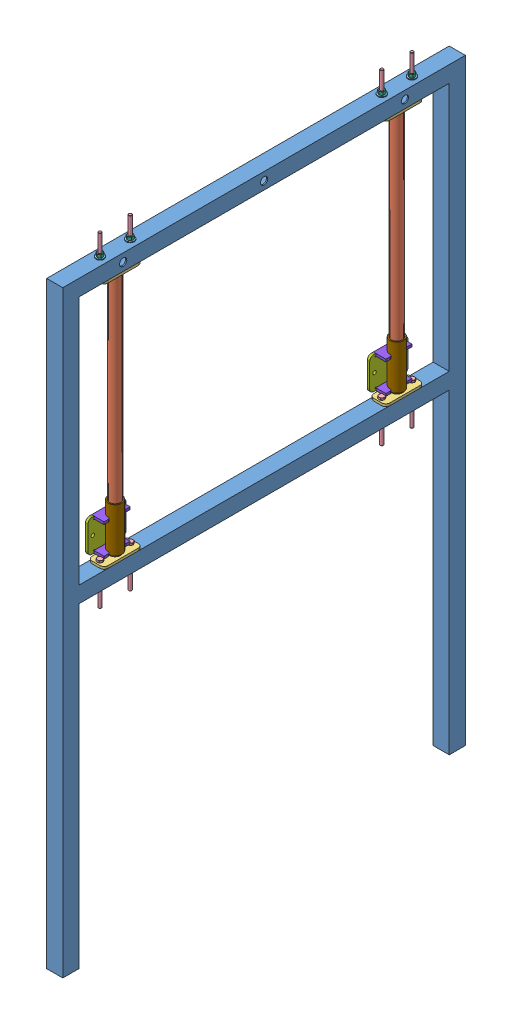
SolidWorks assembly Side frame asm, configuration Default. Lengths in mm.
Overall size (46 1539 1000).
40 component instances, 9 part files, 3 mates.
Components (placement in the parent):
- Side frame sub asm-1: Side frame sub asm [Default] at (-148.9643 -90.3004 178.1954) size (40 1539 1000)
  - Side frame-1: Side frame [Default] at (665 0 0) x (0 0 -1) z (1 0 0) size (1000 1485 40)
  - Slider rod-1: Slider rod [Default] at (343.5 40 -330) x (1 0 0) z (0 -1 0) size (27 27 620)
  - Slider rod plate-1: Slider rod plate [Default] at (711 -574 -2.5) x (0 0 -1) z (0 -1 0) size (95 40 6)
  - Slider rod plate-2: Slider rod plate [Default] at (711 40 -2.5) x (0 0 -1) z (0 -1 0) size (95 40 6)
  - Slider rod plate-3: Slider rod plate [Default] at (711 -580 2.5) x (0 0 1) z (0 1 0) size (95 40 6)
  - Slider rod plate-4: Slider rod plate [Default] at (711 34 2.5) x (0 0 1) z (0 1 0) size (95 40 6)
  - Slider rod-2: Slider rod [Default] at (343.5 -580 330) x (1 0 0) z (0 1 0) size (27 27 620)
  - hex bolt gradeab_iso-1: hex bolt gradeab_iso [ISO 4014 - M8 x 100 x 100-N] at (691 28.7 -312.5) x (0 1 0) z (0 0 1) size (105.3 15.01 13)
  - hex bolt gradeab_iso-2: hex bolt gradeab_iso [ISO 4014 - M8 x 100 x 100-N] at (691 28.7 -387.5) x (0 1 0) z (0 0 1) size (105.3 15.01 13)
  - hex bolt gradeab_iso-3: hex bolt gradeab_iso [ISO 4014 - M8 x 100 x 100-N] at (691 -568.7 -312.5) x (0 -1 0) z (0 0 1) size (105.3 15.01 13)
  - hex bolt gradeab_iso-4: hex bolt gradeab_iso [ISO 4014 - M8 x 100 x 100-N] at (691 -568.7 -387.5) x (0 -1 0) z (0 0 1) size (105.3 15.01 13)
  - plain washer 10669 type nl_iso-1: plain washer 10669 type nl_iso [ISO 10669-8.8-N] at (691 80 -312.5) x (0 1 0) z (0 0 1) size (2 20 20)
  - plain washer 10669 type nl_iso-2: plain washer 10669 type nl_iso [ISO 10669-8.8-N] at (691 80 -387.5) x (0 1 0) z (0 0 1) size (2 20 20)
  - plain washer 10669 type nl_iso-3: plain washer 10669 type nl_iso [ISO 10669-8.8-N] at (691 -620 -312.5) x (0 -1 0) z (0 0 1) size (2 20 20)
  - plain washer 10669 type nl_iso-4: plain washer 10669 type nl_iso [ISO 10669-8.8-N] at (691 -620 -387.5) x (0 -1 0) z (0 0 1) size (2 20 20)
  - hex nut gradec_iso-1: hex nut gradec_iso [ISO - 4034 - M8 - N] at (691 -629.9 -387.5) x (1 0 0) z (0 -1 0) size (13 15.01 7.9)
  - hex nut gradec_iso-2: hex nut gradec_iso [ISO - 4034 - M8 - N] at (691 -629.9 -312.5) x (1 0 0) z (0 -1 0) size (13 15.01 7.9)
  - hex nut gradec_iso-3: hex nut gradec_iso [ISO - 4034 - M8 - N] at (691 89.9 -312.5) x (1 0 0) z (0 1 0) size (13 15.01 7.9)
  - hex nut gradec_iso-4: hex nut gradec_iso [ISO - 4034 - M8 - N] at (691 89.9 -387.5) x (1 0 0) z (0 1 0) size (13 15.01 7.9)
  - hex bolt gradeab_iso-5: hex bolt gradeab_iso [ISO 4014 - M8 x 100 x 100-N] at (691 28.7 387.5) x (0 1 0) z (0 0 1) size (105.3 15.01 13)
  - hex bolt gradeab_iso-6: hex bolt gradeab_iso [ISO 4014 - M8 x 100 x 100-N] at (691 -568.7 312.5) x (0 -1 0) z (0 0 1) size (105.3 15.01 13)
  - hex bolt gradeab_iso-7: hex bolt gradeab_iso [ISO 4014 - M8 x 100 x 100-N] at (691 -568.7 387.5) x (0 -1 0) z (0 0 1) size (105.3 15.01 13)
  - plain washer 10669 type nl_iso-5: plain washer 10669 type nl_iso [ISO 10669-8.8-N] at (691 80 312.5) x (0 1 0) z (0 0 1) size (2 20 20)
  - plain washer 10669 type nl_iso-6: plain washer 10669 type nl_iso [ISO 10669-8.8-N] at (691 80 387.5) x (0 1 0) z (0 0 1) size (2 20 20)
  - plain washer 10669 type nl_iso-7: plain washer 10669 type nl_iso [ISO 10669-8.8-N] at (691 -620 312.5) x (0 -1 0) z (0 0 1) size (2 20 20)
  - plain washer 10669 type nl_iso-8: plain washer 10669 type nl_iso [ISO 10669-8.8-N] at (691 -620 387.5) x (0 -1 0) z (0 0 1) size (2 20 20)
  - hex nut gradec_iso-5: hex nut gradec_iso [ISO - 4034 - M8 - N] at (691 -622 387.5) x (1 0 0) z (0 1 0) size (13 15.01 7.9)
  - hex nut gradec_iso-6: hex nut gradec_iso [ISO - 4034 - M8 - N] at (691 -622 312.5) x (1 0 0) z (0 1 0) size (13 15.01 7.9)
  - hex nut gradec_iso-7: hex nut gradec_iso [ISO - 4034 - M8 - N] at (691 82 387.5) x (1 0 0) z (0 -1 0) size (13 15.01 7.9)
  - hex bolt gradeab_iso-8: hex bolt gradeab_iso [ISO 4014 - M8 x 100 x 100-N] at (691 28.7 312.5) x (0 1 0) z (0 0 1) size (105.3 15.01 13)
  - hex nut gradec_iso-8: hex nut gradec_iso [ISO - 4034 - M8 - N] at (691 82 312.5) x (1 0 0) z (0 -1 0) size (13 15.01 7.9)
- Slider bracket-1: Slider bracket [Default] at (-148.9643 -510.7439 178.1954) size (43 110 95)
  - Guide plate coldpress-1: Guide plate coldpress [Default] at (671 -169.5566 -2.5) x (0 0 1) z (-1 0 0) size (95 80 6)
  - Guide bracket-1: Guide bracket [Default] at (665 -169.5566 -697.5) x (0 0 -1) z (1 0 0) size (65 80 31)
  - Slider tube-1: Slider tube [Default] at (665 -149.5566 -697.5) x (0 0 1) z (0 -1 0) size (34 34 110)
- Slider bracket-2: Slider bracket [Default] at (-148.9643 -510.7439 878.1954) size (43 110 95)
  - Guide plate coldpress-1: Guide plate coldpress [Default] at (671 -169.5566 -2.5) x (0 0 1) z (-1 0 0) size (95 80 6)
  - Guide bracket-1: Guide bracket [Default] at (665 -169.5566 -697.5) x (0 0 -1) z (1 0 0) size (65 80 31)
  - Slider tube-1: Slider tube [Default] at (665 -149.5566 -697.5) x (0 0 1) z (0 -1 0) size (34 34 110)
Mates (geometry in assembly coordinates):
- Concentric6: concentric: cylinder of Side frame sub asm-1/Slider rod-1 through (542.0357 -670.3004 -171.8046) axis (0 1 0) radius 13.5; cylinder of Slider bracket-1/Guide bracket-1 through (542.0357 -580.3004 -171.8046) axis (0 -1 0) radius 17
- Concentric7: concentric: cylinder of Side frame sub asm-1/Side frame-1 through (542.0357 -1495.3004 -134.3046) axis (0 1 0) radius 5; cylinder of Side frame sub asm-1/plain washer 10669 type nl_iso-1 through (542.0357 -8.3004 -134.3046) axis (0 -1 0) radius 4.4
- Coincident1: coincident: plane of Side frame sub asm-1/Side frame-1 through (562.0357 -10.3004 178.1954) normal (0 1 0); plane of Side frame sub asm-1/plain washer 10669 type nl_iso-1 through (542.0357 -10.3004 -134.3046) normal (0 -1 0)
